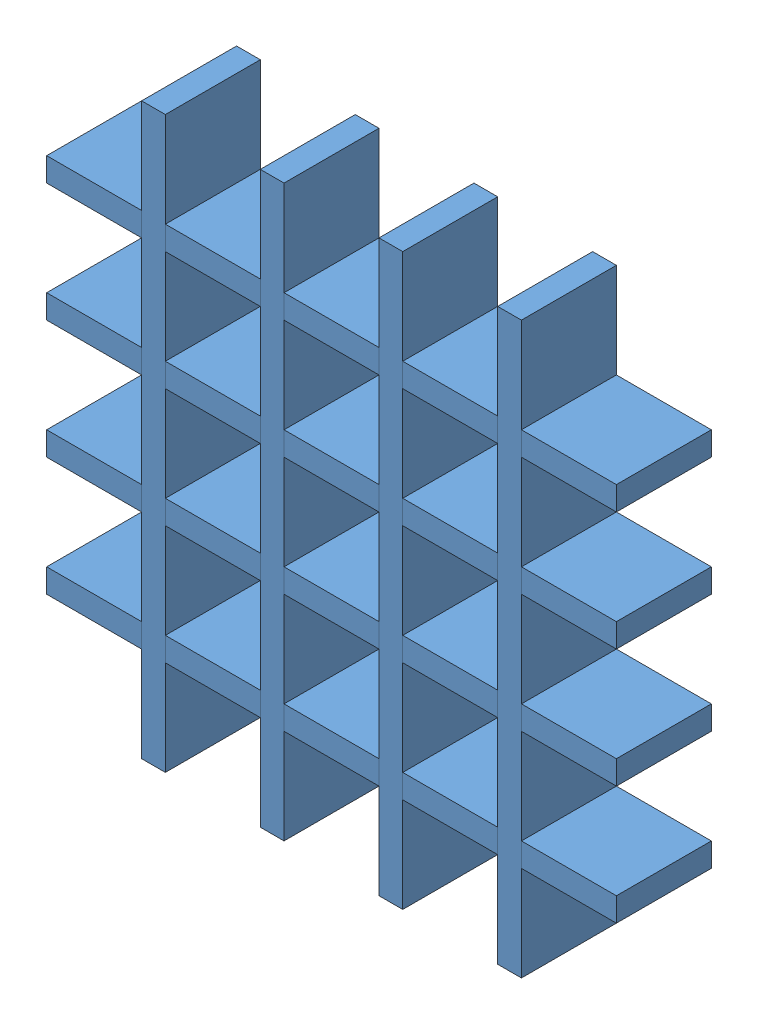
SolidWorks assembly grid_wall_5_5, configuration Default. Lengths in mm.
Overall size (76.2 76.2 12.7).
8 component instances, 1 part files, 21 mates.
Components (placement in the parent):
- divider_wall_5_0_5_0_5-1: divider_wall_5_0_5_0_5 [Default] at (-18.9925 51.9886 61.0854) size (76.2 3.17 12.7)
- divider_wall_5_0_5_0_5-4: divider_wall_5_0_5_0_5 [Default] at (41.3325 -8.3364 73.7854) x (0 1 0) z (0 0 -1) size (76.2 3.17 12.7)
- divider_wall_5_0_5_0_5-5: divider_wall_5_0_5_0_5 [Default] at (-18.9925 36.1136 61.0854) size (76.2 3.17 12.7)
- divider_wall_5_0_5_0_5-6: divider_wall_5_0_5_0_5 [Default] at (-18.9925 20.2386 61.0854) size (76.2 3.17 12.7)
- divider_wall_5_0_5_0_5-7: divider_wall_5_0_5_0_5 [Default] at (-18.9925 4.3636 61.0854) size (76.2 3.17 12.7)
- divider_wall_5_0_5_0_5-8: divider_wall_5_0_5_0_5 [Default] at (-3.1175 67.8636 73.7854) x (0 -1 0) z (0 0 -1) size (76.2 3.17 12.7)
- divider_wall_5_0_5_0_5-9: divider_wall_5_0_5_0_5 [Default] at (12.7575 67.8636 73.7854) x (0 -1 0) z (0 0 -1) size (76.2 3.17 12.7)
- divider_wall_5_0_5_0_5-10: divider_wall_5_0_5_0_5 [Default] at (28.6325 67.8636 73.7854) x (0 -1 0) z (0 0 -1) size (76.2 3.17 12.7)
Mates (geometry in assembly coordinates):
- Coincident1: coincident anti-aligned: plane of divider_wall_5_0_5_0_5-1 through (41.3325 51.9886 67.4354) normal (0 0 1); plane of divider_wall_5_0_5_0_5-4 through (41.3325 51.9886 67.4354) normal (0 0 -1)
- Coincident2: coincident anti-aligned: plane of divider_wall_5_0_5_0_5-1 through (-18.9925 55.1636 61.0854) normal (0 1 0); plane of divider_wall_5_0_5_0_5-4 through (41.3325 55.1636 67.4354) normal (0 -1 0)
- Coincident3: coincident anti-aligned: plane of divider_wall_5_0_5_0_5-1 through (44.5075 51.9886 67.4354) normal (-1 0 0); plane of divider_wall_5_0_5_0_5-4 through (44.5075 -8.3364 73.7854) normal (1 0 0)
- Coincident5: coincident: plane of divider_wall_5_0_5_0_5-4 through (41.3325 36.1136 67.4354) normal (0 0 -1); plane of divider_wall_5_0_5_0_5-5 through (41.3325 36.1136 67.4354) normal (0 0 1)
- Coincident6: coincident: plane of divider_wall_5_0_5_0_5-4 through (41.3325 39.2886 67.4354) normal (0 -1 0); plane of divider_wall_5_0_5_0_5-5 through (-18.9925 39.2886 61.0854) normal (0 1 0)
- Coincident7: coincident anti-aligned: plane of divider_wall_5_0_5_0_5-4 through (44.5075 -8.3364 73.7854) normal (1 0 0); plane of divider_wall_5_0_5_0_5-5 through (44.5075 36.1136 67.4354) normal (-1 0 0)
- Coincident8: coincident: plane of divider_wall_5_0_5_0_5-4 through (44.5075 -8.3364 73.7854) normal (1 0 0); plane of divider_wall_5_0_5_0_5-6 through (44.5075 20.2386 67.4354) normal (-1 0 0)
- Coincident9: coincident: plane of divider_wall_5_0_5_0_5-4 through (41.3325 20.2386 67.4354) normal (0 0 -1); plane of divider_wall_5_0_5_0_5-6 through (41.3325 20.2386 67.4354) normal (0 0 1)
- Coincident10: coincident anti-aligned: plane of divider_wall_5_0_5_0_5-4 through (41.3325 23.4136 67.4354) normal (0 -1 0); plane of divider_wall_5_0_5_0_5-6 through (-18.9925 23.4136 61.0854) normal (0 1 0)
- Coincident11: coincident: plane of divider_wall_5_0_5_0_5-4 through (41.3325 4.3636 67.4354) normal (0 0 -1); plane of divider_wall_5_0_5_0_5-7 through (41.3325 4.3636 67.4354) normal (0 0 1)
- Coincident12: coincident: plane of divider_wall_5_0_5_0_5-4 through (44.5075 -8.3364 73.7854) normal (1 0 0); plane of divider_wall_5_0_5_0_5-7 through (44.5075 4.3636 67.4354) normal (-1 0 0)
- Coincident13: coincident anti-aligned: plane of divider_wall_5_0_5_0_5-4 through (41.3325 7.5386 67.4354) normal (0 -1 0); plane of divider_wall_5_0_5_0_5-7 through (-18.9925 7.5386 61.0854) normal (0 1 0)
- Coincident14: coincident: plane of divider_wall_5_0_5_0_5-1 through (25.4575 51.9886 67.4354) normal (0 0 1); plane of divider_wall_5_0_5_0_5-10 through (28.6325 55.1636 67.4354) normal (0 0 -1)
- Coincident15: coincident: plane of divider_wall_5_0_5_0_5-1 through (25.4575 51.9886 67.4354) normal (1 0 0); plane of divider_wall_5_0_5_0_5-10 through (25.4575 67.8636 73.7854) normal (-1 0 0)
- Coincident16: coincident anti-aligned: plane of divider_wall_5_0_5_0_5-1 through (-18.9925 51.9886 61.0854) normal (0 -1 0); plane of divider_wall_5_0_5_0_5-10 through (28.6325 51.9886 67.4354) normal (0 1 0)
- Coincident17: coincident: plane of divider_wall_5_0_5_0_5-1 through (9.5825 51.9886 67.4354) normal (0 0 1); plane of divider_wall_5_0_5_0_5-9 through (12.7575 55.1636 67.4354) normal (0 0 -1)
- Coincident18: coincident: plane of divider_wall_5_0_5_0_5-1 through (12.7575 51.9886 67.4354) normal (-1 0 0); plane of divider_wall_5_0_5_0_5-9 through (12.7575 67.8636 73.7854) normal (1 0 0)
- Coincident19: coincident anti-aligned: plane of divider_wall_5_0_5_0_5-1 through (-18.9925 51.9886 61.0854) normal (0 -1 0); plane of divider_wall_5_0_5_0_5-9 through (12.7575 51.9886 67.4354) normal (0 1 0)
- Coincident20: coincident: plane of divider_wall_5_0_5_0_5-1 through (-6.2925 51.9886 67.4354) normal (0 0 1); plane of divider_wall_5_0_5_0_5-8 through (-3.1175 55.1636 67.4354) normal (0 0 -1)
- Coincident21: coincident: plane of divider_wall_5_0_5_0_5-1 through (-6.2925 51.9886 67.4354) normal (1 0 0); plane of divider_wall_5_0_5_0_5-8 through (-6.2925 67.8636 73.7854) normal (-1 0 0)
- Coincident22: coincident anti-aligned: plane of divider_wall_5_0_5_0_5-1 through (-18.9925 51.9886 61.0854) normal (0 -1 0); plane of divider_wall_5_0_5_0_5-8 through (-3.1175 51.9886 67.4354) normal (0 1 0)
